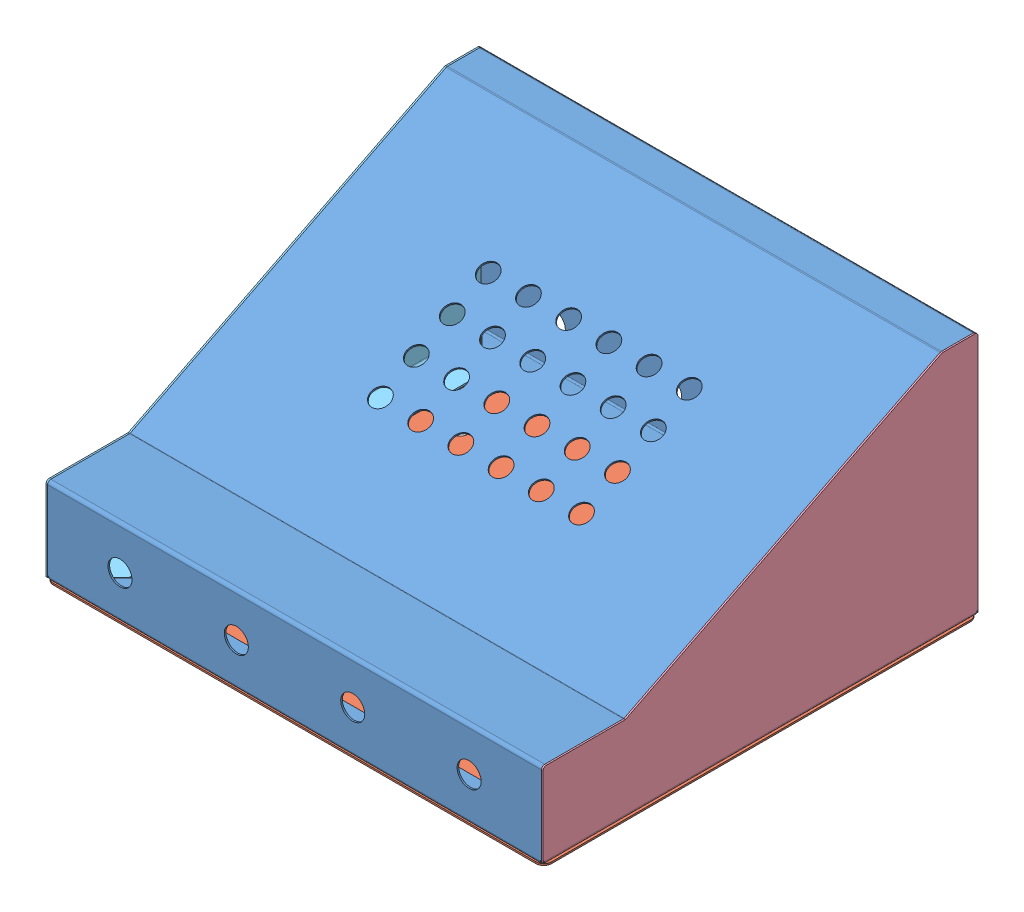
SolidWorks assembly sheet metal box, configuration Default. Lengths in mm.
Overall size (309.8 153.25 286.34).
7 component instances, 5 part files, 18 mates.
Components (placement in the parent):
- sheet_metal_box_PE-1: sheet_metal_box_PE [Default] at (49.4941 80.7463 327.6811) size (307 152.25 270.34)
- base-1: base [Default] at (49.4941 54.4972 192.5121) size (309.8 1 270.34)
- clip-1: clip [Default] at (161.8941 175.4972 42.3421) size (15 22.5 16)
- clip-3: clip [Default] at (161.8941 114.7472 42.3421) size (15 22.5 16)
- clip-4: clip [Default] at (-62.9059 114.7472 42.3421) size (15 22.5 16)
- side cover-1: side cover [Default] at (203.9941 131.2472 192.5121) x (0 0 -1) z (1 0 0) size (270.34 152.25 26)
- side cover left-1: side cover left [Default] at (-104.0059 131.2472 192.5121) x (0 0 -1) z (1 0 0) size (270.34 152.25 26)
Mates (geometry in assembly coordinates):
- Coincident3: coincident aligned: plane of sheet_metal_box_PE-1 through (49.4941 80.7463 57.3421) normal (0 0 -1); plane of base-1 through (204.3941 53.4972 57.3421) normal (0 0 -1)
- Coincident4: coincident aligned: plane of clip-1 through (154.3941 164.2472 57.3421) normal (0 0 1); plane of clip-3 through (169.3941 125.9972 57.3421) normal (0 0 1)
- Coincident5: coincident aligned: plane of clip-1 through (154.3941 164.2472 57.3421) normal (0 0 1); plane of clip-2 through (-70.4059 164.2472 57.3421) normal (0 0 1)
- Coincident6: coincident aligned: plane of clip-3 through (169.3941 125.9972 57.3421) normal (0 0 1); plane of clip-4 through (-55.4059 125.9972 57.3421) normal (0 0 1)
- Coincident7: coincident aligned: plane of clip-1 through (161.8941 186.7472 42.3421) normal (0 1 0); plane of clip-2 through (-62.9059 186.7472 42.3421) normal (0 1 0)
- Coincident8: coincident aligned: plane of clip-1 through (169.3941 164.2472 57.3421) normal (1 0 0); plane of clip-3 through (169.3941 125.9972 42.3421) normal (1 0 0)
- Coincident9: coincident aligned: plane of clip-2 through (-70.4059 164.2472 42.3421) normal (-1 0 0); plane of clip-4 through (-70.4059 125.9972 57.3421) normal (-1 0 0)
- Coincident10: coincident aligned: plane of clip-3 through (161.8941 103.4972 42.3421) normal (0 -1 0); plane of clip-4 through (-62.9059 103.4972 42.3421) normal (0 -1 0)
- Coincident11: coincident anti-aligned: plane of sheet_metal_box_PE-1 through (49.4941 80.7463 57.3421) normal (0 0 -1); plane of clip-1 through (169.3941 186.7472 57.3421) normal (0 0 1)
- Distance2: distance = 35 mm aligned: plane of sheet_metal_box_PE-1 through (-105.4059 205.0106 79.1674) normal (-1 0 0); plane of clip-2 through (-70.4059 165.4972 41.3421) normal (-1 0 0)
- Distance3: distance = 20 mm aligned: plane of sheet_metal_box_PE-1 through (49.4941 206.7472 327.525) normal (0 1 0); plane of clip-2 through (-62.9059 186.7472 42.3421) normal (0 1 0)
- Distance4: distance = 50 mm aligned: plane of base-1 through (49.4941 53.4972 192.5121) normal (0 -1 0); plane of clip-4 through (-62.9059 103.4972 42.3421) normal (0 -1 0)
- Coincident12: coincident anti-aligned: plane of sheet_metal_box_PE-1 through (202.9941 106.8528 276.0572) normal (1 0 0); plane of side cover-1 through (202.9941 131.2472 192.5121) normal (-1 0 0)
- Coincident13: coincident aligned: plane of sheet_metal_box_PE-1 through (49.4941 80.7463 57.3421) normal (0 0 -1); plane of side cover-1 through (202.9941 55.7472 57.3421) normal (0 0 -1)
- Coincident14: coincident aligned: plane of sheet_metal_box_PE-1 through (49.4941 54.4972 327.6811) normal (0 -1 0); plane of side cover-1 through (203.9941 54.4972 192.5121) normal (0 -1 0)
- Coincident18: coincident aligned: plane of sheet_metal_box_PE-1 through (49.4941 80.7463 57.3421) normal (0 0 -1); plane of side cover left-1 through (-105.0059 55.7472 57.3421) normal (0 0 -1)
- Coincident19: coincident aligned: plane of sheet_metal_box_PE-1 through (49.4941 54.4972 327.6811) normal (0 -1 0); plane of side cover left-1 through (-104.0059 54.4972 192.5121) normal (0 -1 0)
- Coincident20: coincident anti-aligned: plane of sheet_metal_box_PE-1 through (-104.0059 205.7472 57.3421) normal (-1 0 0); plane of side cover left-1 through (-104.0059 131.2472 192.5121) normal (1 0 0)
